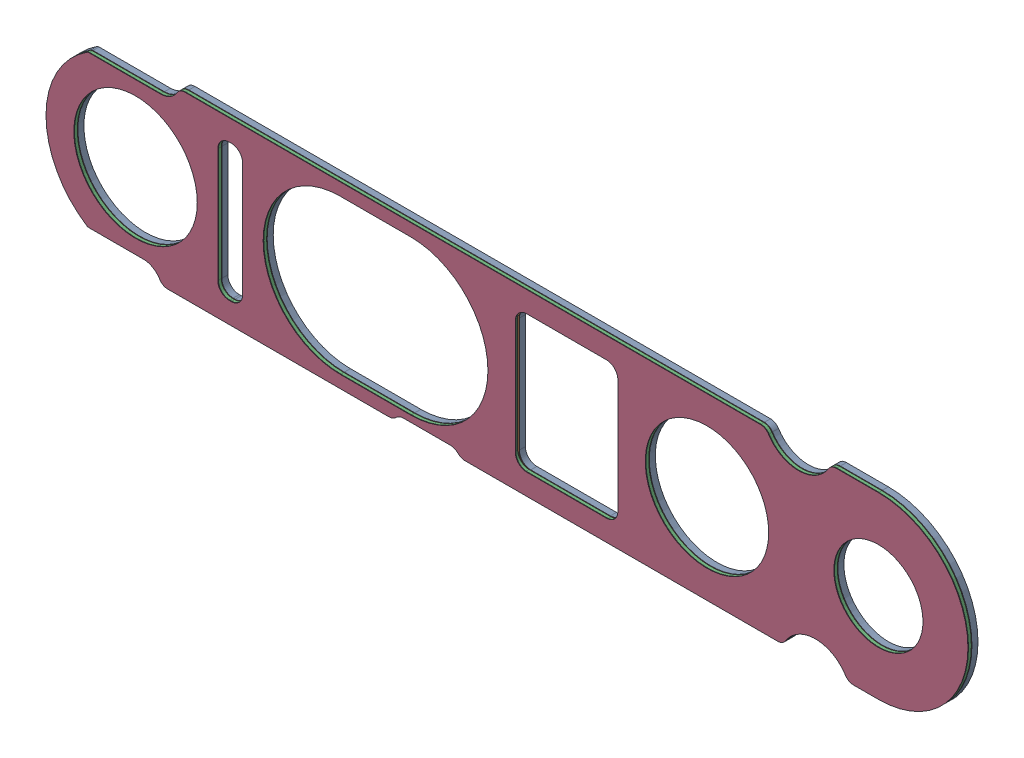
SolidWorks assembly FOAM_ISOLATION_CARRIER_AWG_RGB__ASM, configuration Default. Lengths in mm.
Overall size (80.67 15.67 0.88).
4 component instances, 3 part files, 0 mates.
Components (placement in the parent):
- AWG_FOAM_FRONT_BEZEL_RIGHT_49-1: AWG_FOAM_FRONT_BEZEL_RIGHT_49 [Default] at origin size (80.67 15.67 0.53)
- AWG_ADHESIVE_FRONT_BEZEL_1_18-1: AWG_ADHESIVE_FRONT_BEZEL_1_18 [Default] at origin size (80.67 15.67 0.05)
- AWG_STIFFENER_FRONT_BEZEL_1_18-1: AWG_STIFFENER_FRONT_BEZEL_1_18 [Default] at (0 0 0.25) size (80.67 15.67 0.25)
- AWG_ADHESIVE_FRONT_BEZEL_1_18-2: AWG_ADHESIVE_FRONT_BEZEL_1_18 [Default] at (0 0 0.3) size (80.67 15.67 0.05)
